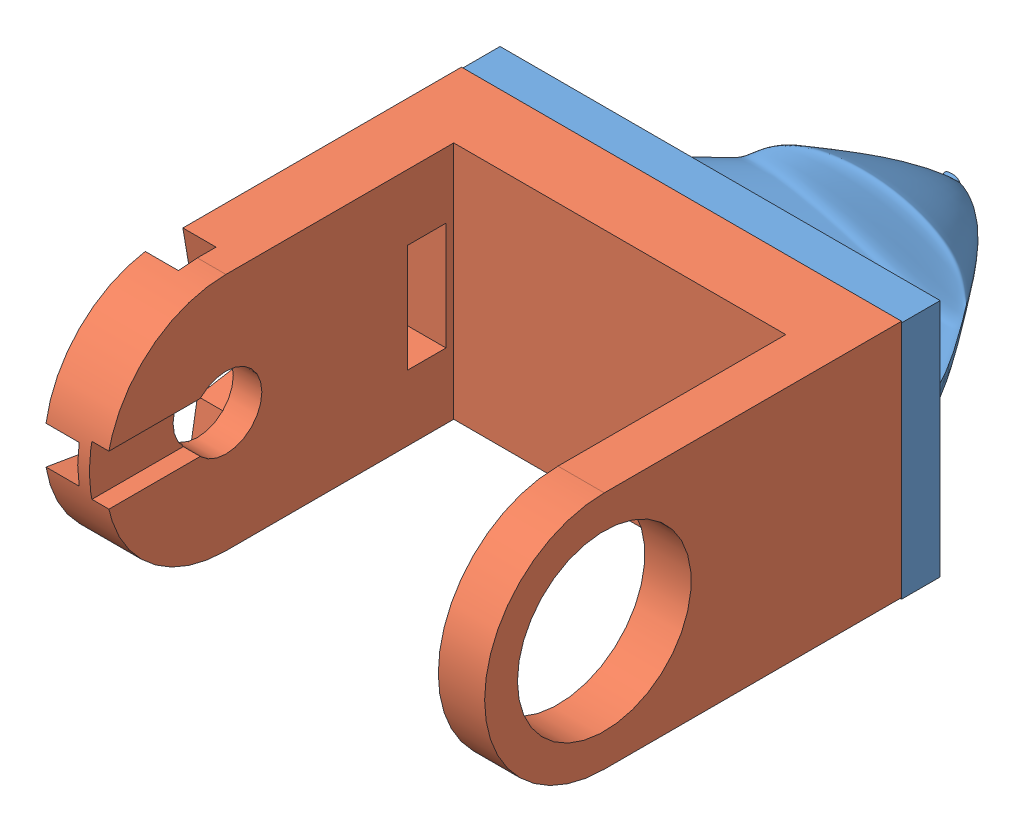
SolidWorks assembly Assem2, configuration Default. Lengths in mm.
Overall size (57 31.24 89.06).
2 component instances, 2 part files, 3 mates.
Components (placement in the parent):
- Head Cap-1: Head Cap [Default] at (21.9586 34.8973 52.4211) size (57 31.11 35.06)
- Nose servo mount-1: Nose servo mount [Default] at (21.9586 35.0808 66.4211) x (0 -1 0) z (0 0 -1) size (31 57 54)
Mates (geometry in assembly coordinates):
- Coincident4: coincident: plane of Head Cap-1 through (50.4586 19.3973 57.4211) normal (1 0 0); plane of Nose servo mount-1 through (50.4586 19.5808 57.4211) normal (1 0 0)
- Coincident5: coincident: plane of Head Cap-1 through (21.9586 34.8973 57.4211) normal (0 0 1); plane of Nose servo mount-1 through (21.9586 35.0808 57.4211) normal (0 0 -1)
- Concentric1: concentric anti-aligned: circle of Head Cap-1; circle of Nose servo mount-1
